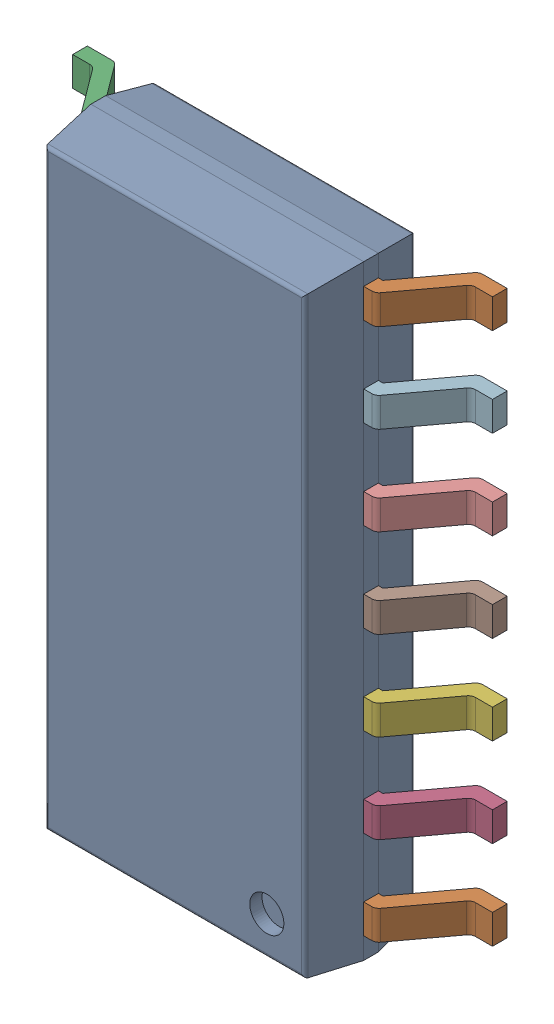
SolidWorks assembly IC11_IC104_1.step, configuration Default. Lengths in mm.
Overall size (6 8.65 1.75).
3 component instances, 2 part files, 0 mates.
Components (placement in the parent):
- 6348793888_1.step-11: 6348793888_1.step [Default] at (521.774 251.303 0) x (-1 0 0) z (0 0 1) size (6 8.65 1.75)
  - Body-16_1.step-54: Body-16_1.step [Default] at origin size (3.9 8.65 1.57)
  - PinsArrayLR-17_1.step-54: PinsArrayLR-17_1.step [Default] at origin size (6 8.04 1)
